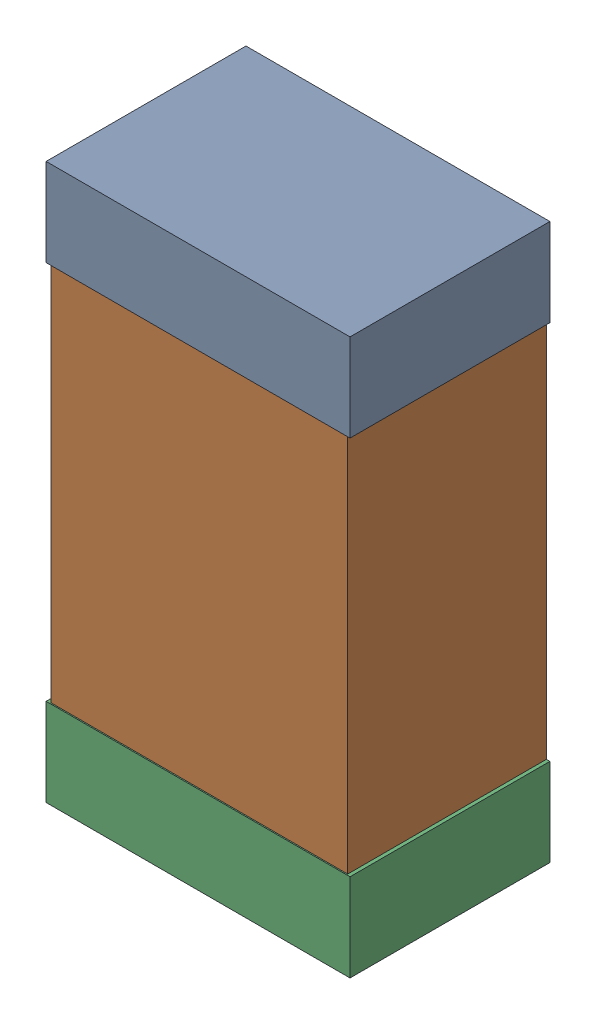
SolidWorks assembly C2Kanaloa_v2.0.0_GPIO_b, configuration Default. Lengths in mm.
Overall size (1.3 2.38 0.85).
6 component instances, 2 part files, 0 mates.
Components (placement in the parent):
- 330415056-1: 330415056 [Default] at (81.534 77.327 0) size (1.3 0.38 0.85)
  - Extruded_2-1: Extruded_2 [Default] at origin size (1.3 0.38 0.85)
- 352877008-1: 352877008 [Default] at (81.534 76.327 0) size (1.27 2.2 0.85)
  - Extruded_3-1: Extruded_3 [Default] at origin size (1.27 2.2 0.85)
- 330415056-2: 330415056 [Default] at (81.534 75.327 0) size (1.3 0.38 0.85)
  - Extruded_2-1: Extruded_2 [Default] at origin size (1.3 0.38 0.85)
